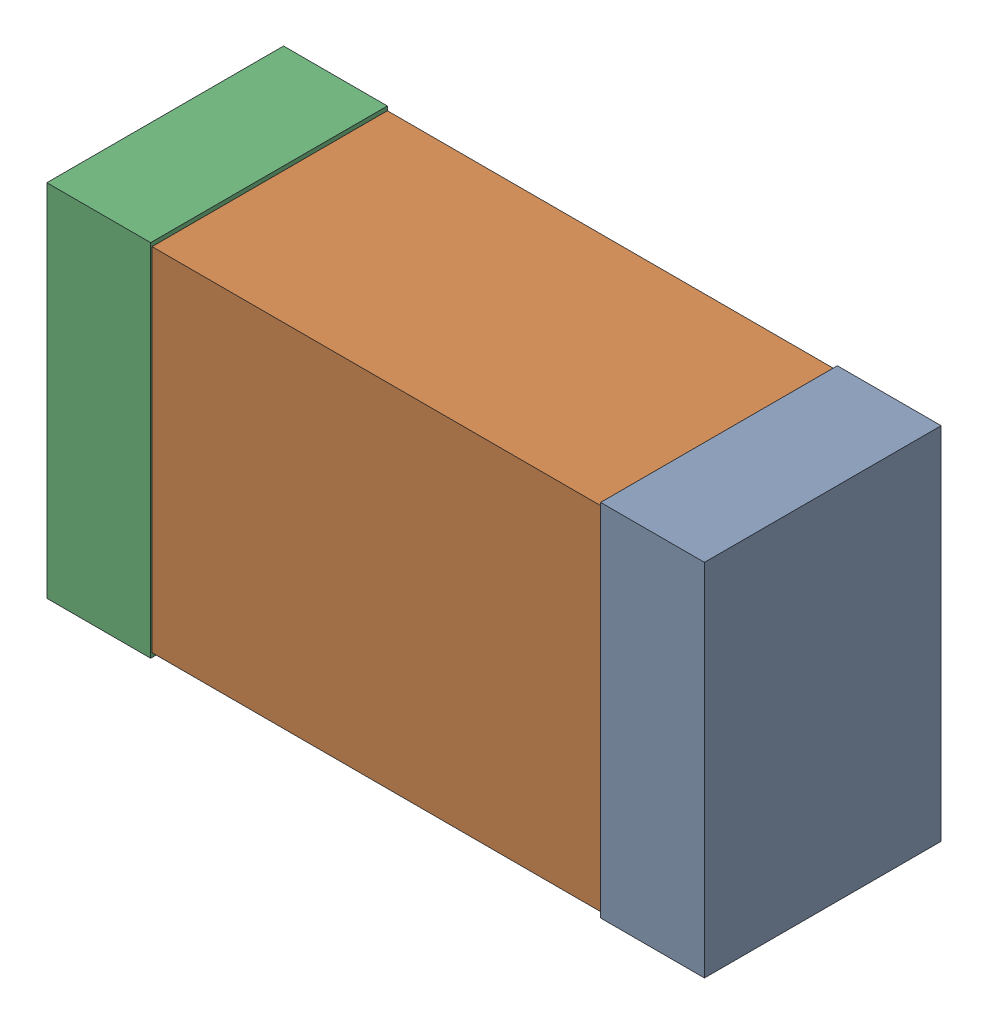
SolidWorks assembly 3300pFKanaloa_v2.0.0_Power, configuration Default. Lengths in mm.
Overall size (2.38 1.3 0.85).
6 component instances, 2 part files, 0 mates.
Components (placement in the parent):
- 352877648-1: 352877648 [Default] at (139.3168 88.1554 0) size (0.38 1.3 0.85)
  - Extruded_14-1: Extruded_14 [Default] at origin size (0.38 1.3 0.85)
- 352877392-1: 352877392 [Default] at (138.3168 88.1554 0) size (2.2 1.27 0.85)
  - Extruded_15-1: Extruded_15 [Default] at origin size (2.2 1.27 0.85)
- 352877648-2: 352877648 [Default] at (137.3168 88.1554 0) size (0.38 1.3 0.85)
  - Extruded_14-1: Extruded_14 [Default] at origin size (0.38 1.3 0.85)
